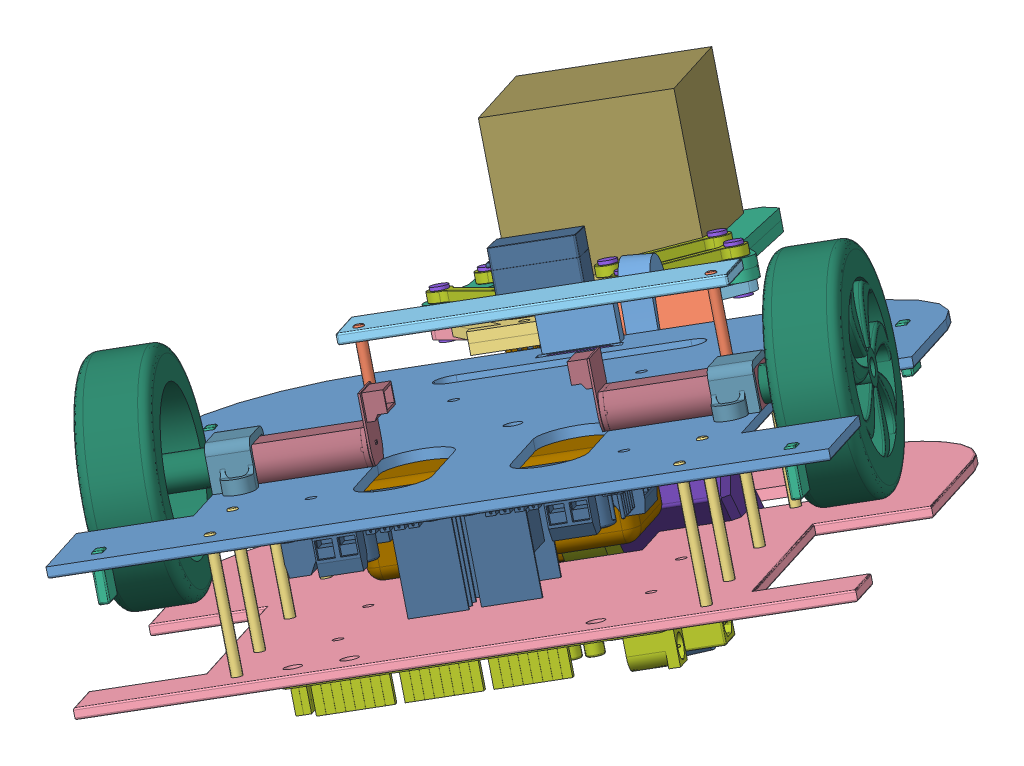
SolidWorks assembly body_3, configuration Default. Lengths in mm.
Overall size (352.49 285.44 388.81).
84 component instances, 30 part files, 44 mates.
Components (placement in the parent):
- Bottom-1: Bottom [Default] at (240.0196 -450.3378 91.3935) x (-0.748912 -0.245301 0.615596) z (0.507001 0.38608 0.770644) size (200 13 200)
- IR spacer-1: IR spacer [Default] at (239.1963 -439.4844 21.6169) x (0.47109 0.063028 -0.87983) z (-0.772006 -0.453054 -0.445813) size (3 25 3)
- IR spacer-3: IR spacer [Default] at (171.7942 -461.5615 77.0205) x (-0.891758 -0.383365 0.240414) z (0.150621 0.249523 0.956583) size (3 25 3)
- spacer-1: spacer [Default] at (180.6754 -475.4215 106.6688) x (-0.764646 -0.452027 -0.459335) z (-0.482946 -0.07001 0.872847) size (3 40 3)
- spacer-2: spacer [Default] at (222.0799 -492.4598 150.2506) x (0.374411 0.339543 0.86286) z (-0.823247 -0.306498 0.477832) size (3 40 3)
- spacer-3: spacer [Default] at (257.57 -465.4342 204.1957) x (0.903913 0.413434 -0.109611) z (0.029349 0.195711 0.980222) size (3 40 3)
- spacer-4: spacer [Default] at (242.3599 -477.0166 181.0764) x (0.903814 0.412806 -0.112741) z (0.032236 0.19703 0.979867) size (3 40 3)
- spacer-5: spacer [Default] at (332.2294 -447.5805 107.2049) x (-0.365654 -0.003 0.930746) z (-0.827174 -0.457407 -0.326439) size (3 40 3)
- spacer-6: spacer [Default] at (311.9493 -463.0237 76.3791) x (0.625269 0.42171 0.656658) z (-0.65342 -0.177175 0.735969) size (3 40 3)
- spacer-7: spacer [Default] at (270.5449 -445.9854 32.7973) x (-0.164362 -0.255408 -0.95276) z (-0.889328 -0.379469 0.255144) size (3 40 3)
- spacer-8: spacer [Default] at (347.4394 -435.9981 130.3242) x (-0.36301 -0.001539 0.931784) z (-0.828337 -0.457414 -0.323464) size (3 40 3)
- top final-1: top final [Default] at (255.3811 -482.3509 97.3253) x (-0.748912 -0.245301 0.615596) z (0.507001 0.38608 0.770644) size (200 13 200)
- IR panel-1: IR panel [Default] at (204.4537 -455.5657 46.0422) x (0.748912 0.245301 -0.615596) z (0.507001 0.38608 0.770644) size (100 3 20)
- t sensor-1: t sensor [Default] at (148.2719 -499.2141 101.6269) x (-0.507001 -0.38608 -0.770644) z (-0.426709 0.889252 -0.164772) size (10 3 13)
- t sensor-2: t sensor [Default] at (220.5544 -443.1963 216.7584) x (0.507001 0.38608 0.770644) z (-0.426709 0.889252 -0.164772) size (10 3 13)
- t sensor-3: t sensor [Default] at (355.3585 -399.0421 105.9511) x (-0.507001 -0.38608 -0.770644) z (-0.426709 0.889252 -0.164772) size (10 3 13)
- t sensor-4: t sensor [Default] at (278.5826 -456.5317 -5.4867) x (0.507001 0.38608 0.770644) z (-0.426709 0.889252 -0.164772) size (10 3 13)
- ARDUINO MEGA-1: ARDUINO MEGA [Default] at (293.8708 -457.8048 148.3281) x (-0.748912 -0.245301 0.615596) z (0.507001 0.38608 0.770644) size (108 12.8 52)
- tcs34725-1: tcs34725 [Default] at (200.1491 -492.8286 26.0185) x (-0.748912 -0.245301 0.615596) z (0.426709 -0.889252 0.164772) size (20.3 2.67 20)
- batt-1: batt [Default] at (270.664 -428.9031 145.9212) x (0.507001 0.38608 0.770644) z (0.748912 0.245301 -0.615596) size (58.61 25 130.11)
- L298N Stepper Motor Driver Assembly-1: L298N Stepper Motor Driver Assembly [Default] at (255.5695 -426.9058 134.486) x (0.507001 0.38608 0.770644) z (0.748912 0.245301 -0.615596) size (43 28.01 43)
  - L298N Stepper Motor Driver (Red)-Part File-1: L298N Stepper Motor Driver (Red)-Part File [Default] at (16.8606 10.1012 32.1341) size (43 28.01 43)
  - pan head cross recess screw_iso_ISO 7045 - M1.6 x 4 - Z - 4N-1: pan head cross recess screw_iso_ISO 7045 - M1.6 x 4 - Z - 4N [Default] at (-1.3394 22.4012 35.9476) x (0 -1 0) z (-0.742963 0 0.669332) size (5.3 3.2 3.23)
  - pan head cross recess screw_iso_ISO 7045 - M1.6 x 4 - Z - 4N-2: pan head cross recess screw_iso_ISO 7045 - M1.6 x 4 - Z - 4N [Default] at (-1.3394 22.4012 41.5921) x (0 -1 0) z (-0.751552 0 0.659674) size (5.3 3.2 3.23)
  - pan head cross recess screw_iso_ISO 7045 - M1.6 x 4 - Z - 4N-3: pan head cross recess screw_iso_ISO 7045 - M1.6 x 4 - Z - 4N [Default] at (3.7852 22.4012 50.3107) x (0 -1 0) z (0.734198 0 -0.678936) size (5.3 3.2 3.23)
  - pan head cross recess screw_iso_ISO 7045 - M1.6 x 4 - Z - 4N-4: pan head cross recess screw_iso_ISO 7045 - M1.6 x 4 - Z - 4N [Default] at (14.2688 22.4012 50.3107) x (0 -1 0) z (0.720108 0 0.693862) size (5.3 3.2 3.23)
  - pan head cross recess screw_iso_ISO 7045 - M1.6 x 4 - Z - 4N-5: pan head cross recess screw_iso_ISO 7045 - M1.6 x 4 - Z - 4N [Default] at (9.027 22.4012 50.3107) x (0 -1 0) z (0.308372 0 0.951266) size (5.3 3.2 3.23)
  - pan head cross recess screw_iso_ISO 7045 - M1.6 x 4 - Z - 4N-6: pan head cross recess screw_iso_ISO 7045 - M1.6 x 4 - Z - 4N [Default] at (33.6606 22.4012 35.9476) x (0 -1 0) z (0 0 1) size (5.3 3.2 3.23)
  - pan head cross recess screw_iso_ISO 7045 - M1.6 x 4 - Z - 4N-7: pan head cross recess screw_iso_ISO 7045 - M1.6 x 4 - Z - 4N [Default] at (33.6606 22.4012 41.6421) x (0 -1 0) z (-0.222944 0 0.974831) size (5.3 3.2 3.23)
  - countersunk flat head cross recess screw_iso_ISO 7046-1 - M2.5 x 3 - Z - 3N-1: countersunk flat head cross recess screw_iso_ISO 7046-1 - M2.5 x 3 - Z - 3N [Default] at (16.3567 30.6012 21.6857) x (0 0 -1) z (1 0 0) size (3 4.7 4.7)
- L298N Stepper Motor Driver Assembly-2: L298N Stepper Motor Driver Assembly [Default] at (286.3475 -409.4056 149.2271) x (-0.507001 -0.38608 -0.770644) z (-0.748912 -0.245301 0.615596) size (43 28.01 43)
  - L298N Stepper Motor Driver (Red)-Part File-1: L298N Stepper Motor Driver (Red)-Part File [Default] at (16.8606 10.1012 32.1341) size (43 28.01 43)
  - pan head cross recess screw_iso_ISO 7045 - M1.6 x 4 - Z - 4N-1: pan head cross recess screw_iso_ISO 7045 - M1.6 x 4 - Z - 4N [Default] at (-1.3394 22.4012 35.9476) x (0 -1 0) z (-0.742963 0 0.669332) size (5.3 3.2 3.23)
  - pan head cross recess screw_iso_ISO 7045 - M1.6 x 4 - Z - 4N-2: pan head cross recess screw_iso_ISO 7045 - M1.6 x 4 - Z - 4N [Default] at (-1.3394 22.4012 41.5921) x (0 -1 0) z (-0.751552 0 0.659674) size (5.3 3.2 3.23)
  - pan head cross recess screw_iso_ISO 7045 - M1.6 x 4 - Z - 4N-3: pan head cross recess screw_iso_ISO 7045 - M1.6 x 4 - Z - 4N [Default] at (3.7852 22.4012 50.3107) x (0 -1 0) z (0.734198 0 -0.678936) size (5.3 3.2 3.23)
  - pan head cross recess screw_iso_ISO 7045 - M1.6 x 4 - Z - 4N-4: pan head cross recess screw_iso_ISO 7045 - M1.6 x 4 - Z - 4N [Default] at (14.2688 22.4012 50.3107) x (0 -1 0) z (0.720108 0 0.693862) size (5.3 3.2 3.23)
  - pan head cross recess screw_iso_ISO 7045 - M1.6 x 4 - Z - 4N-5: pan head cross recess screw_iso_ISO 7045 - M1.6 x 4 - Z - 4N [Default] at (9.027 22.4012 50.3107) x (0 -1 0) z (0.308372 0 0.951266) size (5.3 3.2 3.23)
  - pan head cross recess screw_iso_ISO 7045 - M1.6 x 4 - Z - 4N-6: pan head cross recess screw_iso_ISO 7045 - M1.6 x 4 - Z - 4N [Default] at (33.6606 22.4012 35.9476) x (0 -1 0) z (0 0 1) size (5.3 3.2 3.23)
  - pan head cross recess screw_iso_ISO 7045 - M1.6 x 4 - Z - 4N-7: pan head cross recess screw_iso_ISO 7045 - M1.6 x 4 - Z - 4N [Default] at (33.6606 22.4012 41.6421) x (0 -1 0) z (-0.222944 0 0.974831) size (5.3 3.2 3.23)
  - countersunk flat head cross recess screw_iso_ISO 7046-1 - M2.5 x 3 - Z - 3N-1: countersunk flat head cross recess screw_iso_ISO 7046-1 - M2.5 x 3 - Z - 3N [Default] at (16.3567 30.6012 21.6857) x (0 0 -1) z (1 0 0) size (3 4.7 4.7)
- wheel motor assembly-6: wheel motor assembly [Default] at (269.8565 -435.1542 185.6104) x (-0.128378 -0.239904 -0.962271) z (-0.426709 0.889252 -0.164772) size (71.05 85.11 65)
  - micro motor assembly-1: micro motor assembly [Default] at (54.6346 42.2185 20.0539) x (0 -1 0) z (-1 0 0) size (57.18 19.3 37.83)
    - Part1-1: Part1 [Default] x (0.437378 0 0.899278) z (-0.899278 0 0.437378) size (14.6 19.3 56.48)
  - Part2_1-1: Part2_1 [Default] at (46.6525 58.6304 14.7539) x (-0.899278 -0.437378 0) z (-0.437378 0.899278 0) size (29.6 12.6 11.51)
  - wheel1-1: wheel1 [Default] at (31.891 88.981 20.0539) x (-0.899278 -0.437378 0) z (0 0 1) size (65 28.8 65)
- wheel motor assembly-8: wheel motor assembly [Default] at (249.1379 -471.6852 42.1121) x (0.128378 0.239904 0.962271) z (-0.426709 0.889252 -0.164772) size (71.05 85.11 65)
  - micro motor assembly-1: micro motor assembly [Default] at (54.6346 42.2185 20.0539) x (0 -1 0) z (-1 0 0) size (57.18 19.3 37.83)
    - Part1-1: Part1 [Default] x (0.437378 0 0.899278) z (-0.899278 0 0.437378) size (14.6 19.3 56.48)
  - Part2_1-1: Part2_1 [Default] at (46.6525 58.6304 14.7539) x (-0.899278 -0.437378 0) z (-0.437378 0.899278 0) size (29.6 12.6 11.51)
  - wheel1-1: wheel1 [Default] at (31.891 88.981 20.0539) x (-0.899278 -0.437378 0) z (0 0 1) size (65 28.8 65)
- 3D_model assem-1: 3D_model assem [Default] at (183.9064 -480.5986 -9.6953) x (-0.748912 -0.245301 0.615596) z (0.507001 0.38608 0.770644) size (126.43 104.41 272.47) (flexible)
  - Waist_r1-2: Waist_r1 [Default] at (12.283 16.6911 88.1271) size (60 61.78 65.42)
  - Servo Motor MG996R_r1-1: Servo Motor MG996R_r1 [Default] at (-33.917 49.7197 81.4564) x (0 -0.707107 0.707107) z (0 0.707107 0.707107) size (55.8 47.4 20.5)
  - sub_Arm 1-1: sub_Arm 1 [Default] at (8.283 69.7762 36.3148) x (0 0.320217 -0.947344) z (0 -0.947344 -0.320217) size (105 8.09 20)
  - sub_Arm 2-1: sub_Arm 2 [Default] at (8.283 49.3676 -7.8281) x (0 -0.982486 -0.186339) z (0 0.186339 -0.982486) size (100 8 20)
  - Servo Motor Micro  9g-1: Servo Motor Micro  9g [Default] at (-14.017 77.5742 -2.5293) x (0 -0.982486 -0.186339) z (0 -0.186339 0.982486) size (32.6 29.9 12.4)
  - grip_01-1: grip_01 [Default] at (31.383 16.8203 -20.0308) x (1 0 0) z (0 0.999601 0.02825) size (122.25 152.28 29.8) (flexible)
    - Part3-3-1: Part3-3 [Default] at origin size (63.11 62 3)
    - part4-4-1: part4-4 [Default] at (13.5 37.5997 3) x (0 0 1) z (-0.777293 -0.629138 0) size (3 29.07 49.54)
    - part5-5-1: part5-5 [Default] at (-13.5 37.5997 6) x (0 0 -1) z (0.852762 -0.5223 0) size (3 26.63 49.27)
    - Part1-1-1: Part1-1 [Default] at (-37.5961 57.103 0) x (0.375189 0.926948 0) z (0 0 1) size (78.8 28.36 3)
    - Part2-2-1: Part2-2 [Default] at (-5.2398 58 4.5) x (-0.777486 0.6289 0) z (0 0 1) size (38 7 3)
    - Part2-2-2: Part2-2 [Default] at (5.2398 58 4.5) x (0.777487 0.628899 0) z (0 0 1) size (38 7 3)
    - Part1-1-2: Part1-1 [Default] at (37.5961 57.103 3) x (-0.375189 0.926948 0) z (0 0 -1) size (78.8 28.36 3)
    - Part3-3-2: Part3-3 [Default] at (0 0 -3) size (63.11 62 3)
    - Part1-1-3: Part1-1 [Default] at (37.5961 57.103 0) x (-0.375189 0.926948 0) z (0 0 -1) size (78.8 28.36 3)
    - Part1-1-4: Part1-1 [Default] at (-37.5961 57.103 -3) x (0.375189 0.926948 0) z (0 0 1) size (78.8 28.36 3)
    - Part2-2-5: Part2-2 [Default] at (-5.2398 58 -4.5) x (-0.777486 0.6289 0) z (0 0 1) size (38 7 3)
    - Part2-2-6: Part2-2 [Default] at (5.2398 58 -4.5) x (0.777487 0.628899 0) z (0 0 1) size (38 7 3)
    - Part2-2-9: Part2-2 [Default] at (13.5 37.5997 -4.5) x (0.777293 0.629138 0) z (0 0 1) size (38 7 3)
    - Part2-2-10: Part2-2 [Default] at (-13.5 37.5997 -4.5) x (-0.777292 0.62914 0) z (0 0 1) size (38 7 3)
    - Part6-6-1: Part6-6 [Default] at (13.5 37.5997 7) x (1 0 0) z (0 1 0) size (5 14 5)
    - Part6-6-2: Part6-6 [Default] at (-13.5 37.5997 -7) x (-0.923728 -0.383049 0) z (-0.383049 0.923728 0) size (5 14 5)
    - Part6-6-3: Part6-6 [Default] at (-37.5961 57.103 -7) x (-0.923728 -0.383049 0) z (-0.383049 0.923728 0) size (5 14 5)
    - Part6-6-4: Part6-6 [Default] at (-5.2398 58 -7) x (0.923728 0.383049 0) z (0.383049 -0.923728 0) size (5 14 5)
    - Part6-6-5: Part6-6 [Default] at (-29.3419 77.4959 -7) x (0.923728 0.383049 0) z (0.383049 -0.923728 0) size (5 14 5)
    - Part6-6-6: Part6-6 [Default] at (29.3419 77.4959 -7) x (0.923728 0.383049 0) z (0.383049 -0.923728 0) size (5 14 5)
    - Part6-6-7: Part6-6 [Default] at (5.2398 58 -7) x (0.923728 0.383049 0) z (0.383049 -0.923728 0) size (5 14 5)
    - Part6-6-8: Part6-6 [Default] at (37.5961 57.103 -7) x (0.923728 0.383049 0) z (0.383049 -0.923728 0) size (5 14 5)
    - part8-8-1: part8-8 [Default] at (7.5 17.5997 7) x (0 0 -1) z (0.739365 -0.673305 0) size (10.1 17.5 17.5)
    - microservoSG90-1: microservoSG90 [Default] at (2.4 17.5997 -21.2) x (-1 0 0) z (0 1 0) size (32.3 29.8 12.5)
    - help3-1: help3 [Default] at (-17 -5.5 0) x (0 -1 0) z (-1 0 0) size (25 15 3)
  - Servo Motor Micro  9g-2: Servo Motor Micro  9g [Default] at (-13.517 21.6615 -13.0828) x (0 0.982486 0.186339) z (0 0.186339 -0.982486) size (32.6 29.9 12.4)
- box-1: box [Default] at (118.2663 -528.6604 -99.663) x (0.507001 0.38608 0.770644) z (-0.748912 -0.245301 0.615596) size (50 50 50)
Mates (geometry in assembly coordinates):
- Coincident28: coincident anti-aligned: circle of Bottom-1; circle of IR spacer-1
- Concentric13: concentric aligned: cylinder of Bottom-1 through (180.8888 -475.8661 106.7512) axis (0.426709 -0.889252 0.164772) radius 1.5; circle of spacer-1
- Coincident71: coincident anti-aligned: plane of Bottom-1 through (240.0196 -450.3378 91.3935) normal (-0.426709 0.889252 -0.164772); circle of spacer-1
- Concentric14: concentric anti-aligned: cylinder of Bottom-1 through (205.2249 -457.3343 143.7421) axis (0.426709 -0.889252 0.164772) radius 1.5; circle of spacer-2
- Coincident73: coincident anti-aligned: plane of Bottom-1 through (240.0196 -450.3378 91.3935) normal (-0.426709 0.889252 -0.164772); circle of spacer-2
- Concentric15: concentric aligned: cylinder of Bottom-1 through (240.715 -430.3088 197.6872) axis (0.426709 -0.889252 0.164772) radius 1.5; cylinder of spacer-3 through (240.5016 -429.8641 197.6048) axis (0.426709 -0.889252 0.164772) radius 1.5
- Coincident74: coincident anti-aligned: plane of Bottom-1 through (240.0196 -450.3378 91.3935) normal (-0.426709 0.889252 -0.164772); circle of spacer-3
- Coincident75: coincident aligned: cylinder of Bottom-1 through (225.5049 -441.8911 174.5679) axis (0.426709 -0.889252 0.164772) radius 1.5; circle of spacer-4
- Coincident76: coincident anti-aligned: plane of Bottom-1 through (240.0196 -450.3378 91.3935) normal (-0.426709 0.889252 -0.164772); circle of spacer-4
- Coincident85: coincident anti-aligned: circle of IR spacer-3; plane of IR panel-1 through (203.1736 -452.8979 45.5479) normal (-0.426709 0.889252 -0.164772)
- Concentric18: concentric anti-aligned: circle of IR spacer-1; circle of IR panel-1
- Concentric19: concentric anti-aligned: circle of spacer-3; cylinder of top final-1 through (256.0765 -462.3218 203.619) axis (0.426709 -0.889252 0.164772) radius 1.5
- Coincident87: coincident anti-aligned: circle of spacer-1; cylinder of top final-1 through (196.2503 -507.8792 112.683) axis (0.426709 -0.889252 0.164772) radius 1.5
- Coincident88: coincident anti-aligned: circle of spacer-3; plane of top final-1 through (256.6612 -485.0187 97.8196) normal (0.426709 -0.889252 0.164772)
- Parallel18: parallel aligned: plane of Bottom-1 through (217.1086 -438.9278 230.5118) normal (-0.748912 -0.245301 0.615596); plane of t sensor-1 through (146.0252 -499.95 103.4737) normal (-0.748912 -0.245301 0.615596)
- Coincident104: coincident anti-aligned: plane of Bottom-1 through (219.2616 -436.8956 217.6964) normal (0.748912 0.245301 -0.615596); plane of t sensor-2 through (220.5544 -443.1963 216.7584) normal (-0.748912 -0.245301 0.615596)
- Coincident105: coincident anti-aligned: plane of Bottom-1 through (218.9734 -438.0901 211.9964) normal (0.507001 0.38608 0.770644); plane of t sensor-2 through (216.5133 -438.3814 213.7608) normal (-0.507001 -0.38608 -0.770644)
- Coincident106: coincident: plane of Bottom-1 through (240.0196 -450.3378 91.3935) normal (-0.426709 0.889252 -0.164772); line of t sensor-2 through (219.0081 -437.0887 217.311) axis (-0.507001 -0.38608 -0.770644)
- Coincident113: coincident anti-aligned: plane of Bottom-1 through (144.7324 -493.6493 104.4117) normal (-0.507001 -0.38608 -0.770644); plane of t sensor-1 through (146.7658 -492.4688 102.4825) normal (0.507001 0.38608 0.770644)
- Coincident114: coincident anti-aligned: line of Bottom-1 through (142.1974 -495.5797 100.5585) axis (0.507001 0.38608 0.770644); line of t sensor-1 through (144.4789 -493.8424 104.0264) axis (-0.507001 -0.38608 -0.770644)
- Concentric26: concentric anti-aligned: cylinder of IR spacer-3 through (182.4619 -483.7928 81.1398) axis (-0.426709 0.889252 -0.164772) radius 1.5; cylinder of IR panel-1 through (172.0076 -462.0061 77.1029) axis (0.426709 -0.889252 0.164772) radius 1.5
- Coincident127: coincident anti-aligned: plane of top final-1 through (256.6612 -485.0187 97.8196) normal (0.426709 -0.889252 0.164772); plane of ARDUINO MEGA-1 through (313.01 -457.8714 98.4036) normal (-0.426709 0.889252 -0.164772)
- Concentric27: concentric anti-aligned: cylinder of top final-1 through (321.108 -434.0381 145.3679) axis (0.426709 -0.889252 0.164772) radius 2.5; axis of ARDUINO MEGA-1 through (326.1431 -444.5313 147.3122) axis (-0.426709 0.889252 -0.164772)
- Parallel29: parallel aligned: plane of top final-1 through (208.5045 -511.0823 142.559) normal (-0.748912 -0.245301 0.615596); plane of ARDUINO MEGA-1 through (245.8596 -476.5069 171.7293) normal (-0.748912 -0.245301 0.615596)
- Coincident139: coincident anti-aligned: plane of Bottom-1 through (187.6724 -486.6251 31.119) normal (-0.507001 -0.38608 -0.770644); plane of tcs34725-1 through (191.2667 -488.0615 29.474) normal (0.507001 0.38608 0.770644)
- Coincident141: coincident aligned: plane of Bottom-1 through (240.0196 -450.3378 91.3935) normal (-0.426709 0.889252 -0.164772); plane of tcs34725-1 through (200.7442 -482.7068 18.4138) normal (-0.426709 0.889252 -0.164772)
- Distance7: distance = 1 mm: line of Bottom-1 through (203.9076 -485.0545 15.7583) axis (0.507001 0.38608 0.770644); line of tcs34725-1 through (203.7303 -484.3424 17.2687) axis (0.507001 0.38608 0.770644)
- Coincident144: coincident anti-aligned: plane of Bottom-1 through (241.2997 -453.0056 91.8878) normal (0.426709 -0.889252 0.164772); plane of batt-1 through (270.664 -428.9031 145.9212) normal (-0.426709 0.889252 -0.164772)
- Parallel34: parallel aligned: plane of Bottom-1 through (115.7083 -516.1437 76.383) normal (-0.507001 -0.38608 -0.770644); plane of batt-1 through (225.7498 -483.5957 118.7916) normal (-0.507001 -0.38608 -0.770644)
- Distance10: distance = 34 mm: line of Bottom-1 through (219.9239 -446.6962 181.2957) axis (-0.507001 -0.38608 -0.770644); cylinder of batt-1 through (219.7846 -463.9402 112.869) axis (-0.507001 -0.38608 -0.770644) radius 4
- Coincident146: coincident anti-aligned: plane of Bottom-1 through (241.2997 -453.0056 91.8878) normal (0.426709 -0.889252 0.164772); plane of L298N Stepper Motor Driver Assembly-1/L298N Stepper Motor Driver (Red)-Part File-1 through (292.4938 -421.4963 129.3622) normal (-0.426709 0.889252 -0.164772)
- Distance11: distance = 55 mm: line of L298N Stepper Motor Driver Assembly-1/L298N Stepper Motor Driver (Red)-Part File-1 through (297.6948 -424.5231 99.5581) axis (0.507001 0.38608 0.770644); line of Bottom-1 through (346.49 -405.2403 77.26) axis (0.507001 0.38608 0.770644)
- Distance12: distance = 11 mm: line of L298N Stepper Motor Driver Assembly-1/L298N Stepper Motor Driver (Red)-Part File-1 through (319.4959 -407.9217 132.6958) axis (-0.748912 -0.245301 0.615596); line of Bottom-1 through (366.2631 -390.1832 107.3151) axis (-0.748912 -0.245301 0.615596)
- Coincident150: coincident anti-aligned: plane of wheel motor assembly-6/Part2_1-1 through (196.2148 -460.9456 147.5862) normal (0.426709 -0.889252 0.164772); plane of Bottom-1 through (240.0196 -450.3378 91.3935) normal (-0.426709 0.889252 -0.164772)
- Coincident151: coincident aligned: plane of Bottom-1 through (188.0729 -482.93 128.9208) normal (-0.748912 -0.245301 0.615596); plane of wheel motor assembly-6/micro motor assembly-1/Part1-1 through (199.8755 -446.5017 157.7952) normal (-0.748912 -0.245301 0.615596)
- Distance13: distance = 65 mm: line of wheel motor assembly-6/Part2_1-1 through (205.3408 -453.9961 161.4577) axis (0.748912 0.245301 -0.615596); line of Bottom-1 through (365.6109 -387.1998 106.8983) axis (-0.748912 -0.245301 0.615596)
- Coincident152: coincident anti-aligned: plane of Bottom-1 through (240.0196 -450.3378 91.3935) normal (-0.426709 0.889252 -0.164772); plane of wheel motor assembly-8/Part2_1-1 through (301.9243 -425.9471 62.7128) normal (0.426709 -0.889252 0.164772)
- Coincident153: coincident aligned: plane of Bottom-1 through (292.9206 -448.5878 42.7374) normal (0.748912 0.245301 -0.615596); plane of wheel motor assembly-8/micro motor assembly-1/Part1-1 through (298.3349 -417.0242 61.9017) normal (0.748912 0.245301 -0.615596)
- Distance14: distance = 65 mm: line of Bottom-1 through (365.6109 -387.1998 106.8983) axis (-0.748912 -0.245301 0.615596); line of wheel motor assembly-8/Part2_1-1 through (310.1884 -419.654 75.2743) axis (-0.748912 -0.245301 0.615596)
- Coincident154: coincident anti-aligned: plane of Bottom-1 through (241.2997 -453.0056 91.8878) normal (0.426709 -0.889252 0.164772); plane of 3D_model assem-1/Waist_r1-2 through (226.5103 -464.4302 68.5309) normal (-0.426709 0.889252 -0.164772)
- Distance15: distance = 100 mm: line of 3D_model assem-1/Waist_r1-2 through (224.1147 -469.897 63.4381) axis (-0.426709 0.889252 -0.164772); line of Bottom-1 through (161.4594 -481.4669 145.0478) axis (-0.507001 -0.38608 -0.770644)
- Distance16: distance = 100 mm: line of Bottom-1 through (161.4594 -481.4669 145.0478) axis (-0.507001 -0.38608 -0.770644); line of 3D_model assem-1/Waist_r1-2 through (231.4662 -464.2988 74.6124) axis (-0.426709 0.889252 -0.164772)
- Distance17: distance = 32.8411 mm: line of Bottom-1 through (228.2769 -472.6721 19.4749) axis (-0.748912 -0.245301 0.615596); line of 3D_model assem-1/Waist_r1-2 through (224.1147 -469.897 63.4381) axis (-0.426709 0.889252 -0.164772)
- Parallel36: parallel aligned: plane of Bottom-1 through (366.891 -389.8675 107.3926) normal (0.748912 0.245301 -0.615596); plane of box-1 through (118.2663 -528.6604 -99.663) normal (0.748912 0.245301 -0.615596)
